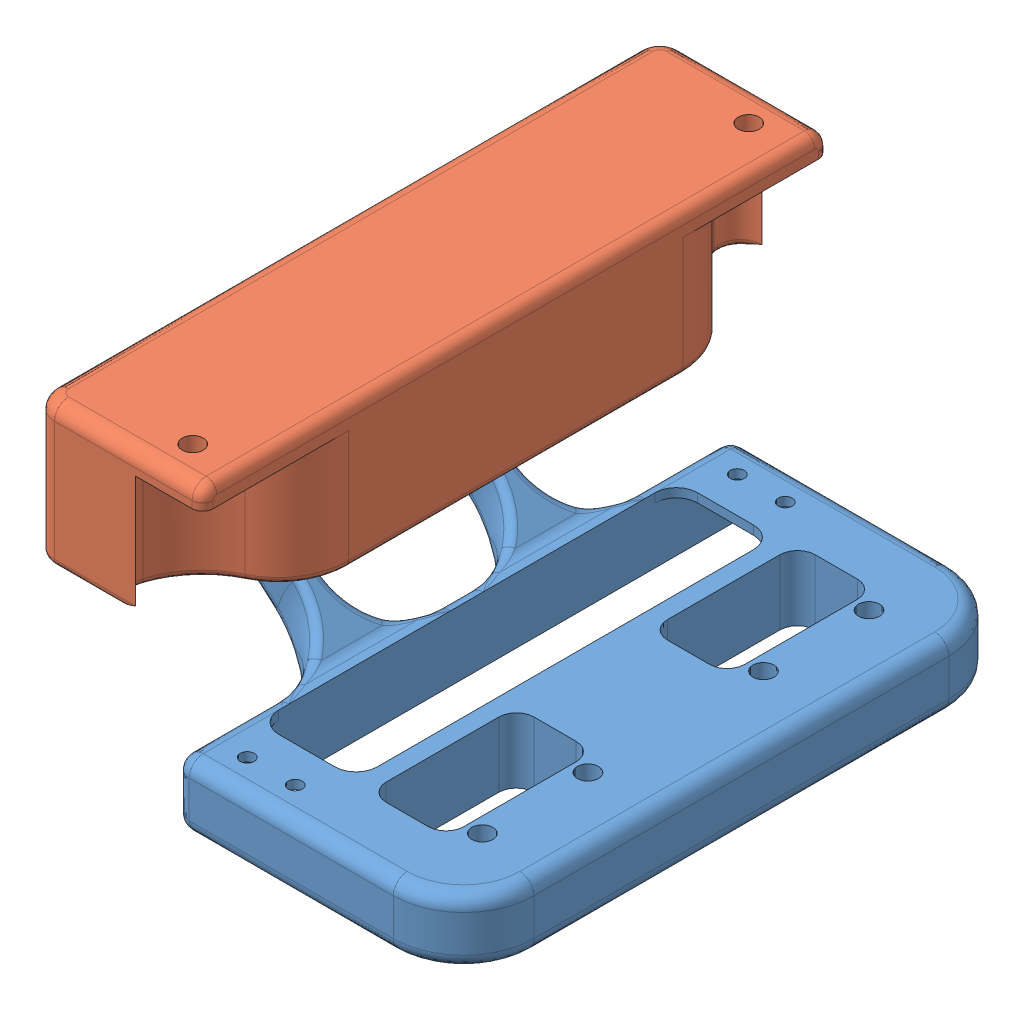
SolidWorks assembly Montagem-Suporte-Sensor, configuration Valor predeterminado. Lengths in mm.
Overall size (66 48.86 89).
2 component instances, 2 part files, 2 mates.
Components (placement in the parent):
- Suporte-Array-Movel-1: Suporte-Array-Movel [Valor predeterminado] at (-27.6262 9.4598 78.95) size (65 25.86 78.95)
- Suporte-Trava-Array-1: Suporte-Trava-Array [Valor predeterminado] at (0.474 32.0324 82.8484) x (0.000123 -1 0) z (0 0 -1) size (30 34.04 89)
Mates (geometry in assembly coordinates):
- Concêntrico2: concentric anti-aligned: circle of Suporte-Array-Movel-1; circle of Suporte-Trava-Array-1
- Distância1: distance = 0.5 mm anti-aligned: plane of Suporte-Trava-Array-1 through (-31.503 32.0284 82.45) normal (0 0 -1); plane of Suporte-Array-Movel-1 through (-27.6262 9.4598 81.95) normal (0 0 1)
